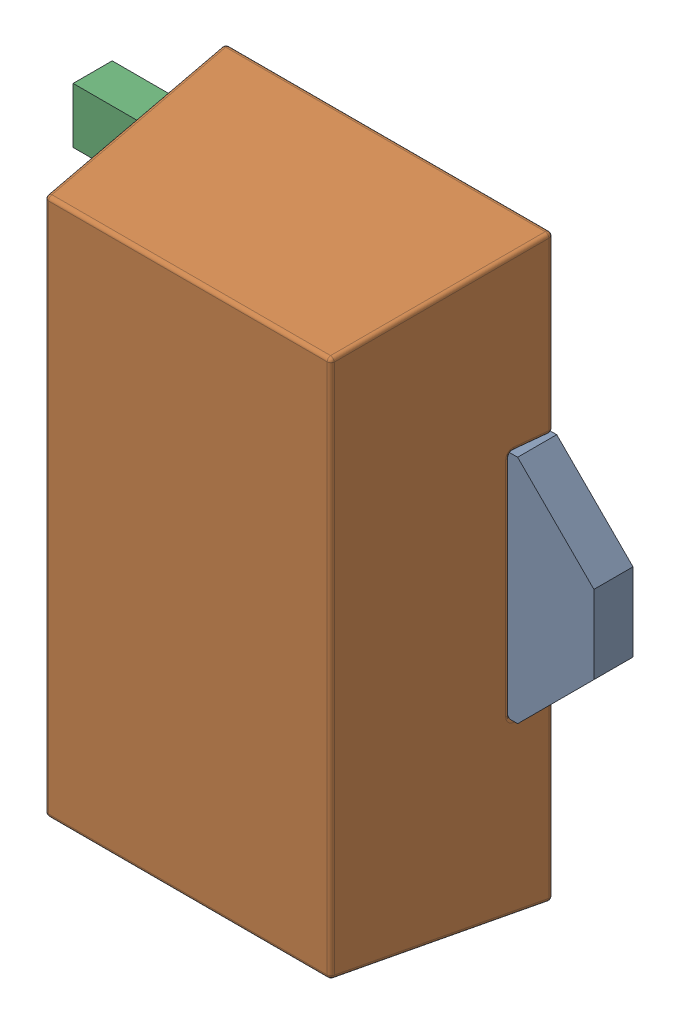
SolidWorks assembly Q80.step, configuration Default. Lengths in mm.
Overall size (4.13 4.59 1.6).
7 component instances, 4 part files, 0 mates.
Components (placement in the parent):
- 6297730608.step-1: 6297730608.step [Default] at (26.289 -10.414 0) x (1 0 0) z (0 0 1) size (4.13 4.59 1.6)
  - CenterLeader.step-1: CenterLeader.step [Default] at (-1.3 -2.3 0) size (4.13 1.83 0.31)
    - Open CASCADE STEP translator 6.8 4.1.1.step-1: Open CASCADE STEP translator 6.8 4.1.1.step [Default] at origin size (4.13 1.83 0.31)
  - Body (9).step-1: Body (9).step [Default] at (-1.3 -2.3 0) size (2.59 4.59 1.6)
    - Open CASCADE STEP translator 6.8 4.4.1.step-1: Open CASCADE STEP translator 6.8 4.4.1.step [Default] at origin size (2.59 4.59 1.6)
  - top.step-1: top.step [Default] at (-1.3 -2.3 0) size (1.2 0.44 0.31)
  - bottom.step-1: bottom.step [Default] at (-1.3 -2.3 0) size (1.2 0.44 0.31)
